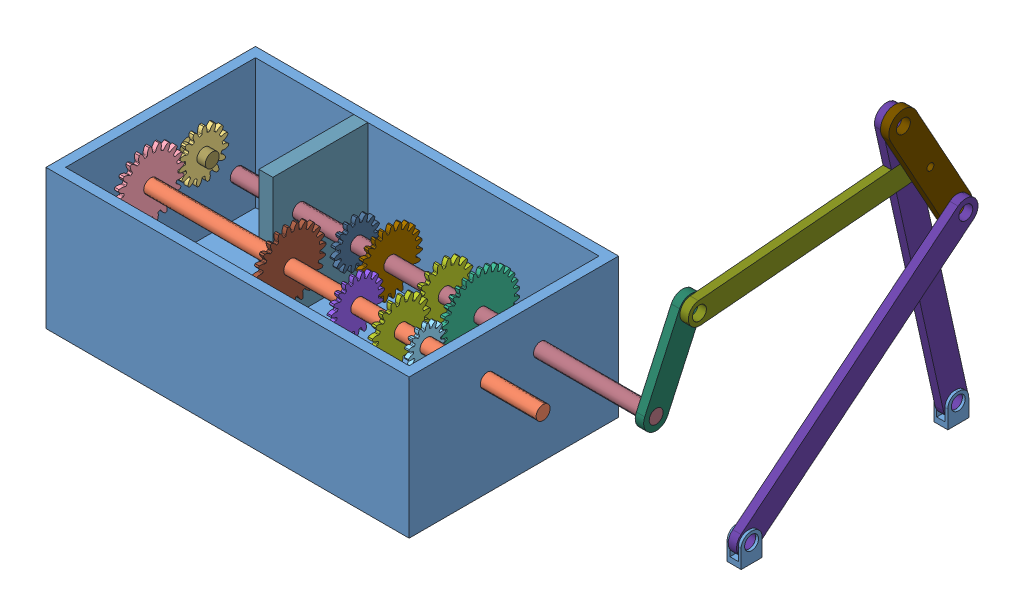
SolidWorks assembly Ensamblaje1 (1), configuration Predeterminado. Lengths in mm.
Overall size (362.85 223.11 312.81).
22 component instances, 19 part files, 42 mates.
Components (placement in the parent):
- caja-1: caja [Predeterminado] at (-217.3634 5.4035 0) size (260 100 150)
- Eje_30cm-1: Eje_30cm [Predeterminado] at (82.6366 25.4035 19.05) x (0 0.184444 0.982843) z (-1 0 0) size (10 10 300)
- E_15_12pd-2: E_15_12pd [Predeterminado] at (-198.3433 25.4035 -19.05) x (0 -0.65131 0.758812) z (-1 0 0) size (35.54 35.73 3)
- E_21_12pd-2: E_21_12pd [Predeterminado] at (-198.3634 25.4035 19.05) x (0 0.948662 0.316291) z (-1 0 0) size (48.58 48.71 3)
- E_14_15pd-2: E_14_15pd [Predeterminado] at (-0.5144 25.4035 19.05) x (0 0.297967 -0.954576) z (-1 0 0) size (26.84 26.84 3)
- E_31_15pd-2: E_31_15pd [Predeterminado] at (-0.1394 25.4035 -19.05) x (0 -0.987554 -0.157277) z (-1 0 0) size (55.79 55.86 3)
- E_18_12pd-1: E_18_12pd [Predeterminado] at (-25.5849 25.4035 -19.05) x (0 0.955422 0.295243) z (-1 0 0) size (42.34 42.34 3)
- E_18_12pd-2: E_18_12pd [Predeterminado] at (-18.9298 25.4035 19.05) x (0 -0.998788 -0.049227) z (-1 0 0) size (42.34 42.34 3)
- E_19_14pd-1: E_19_14pd [Predeterminado] at (-50.071 25.4035 19.05) x (0 -0.854783 0.518986) z (-1 0 0) size (37.93 38.05 3)
- E_23_14pd-1: E_23_14pd [Predeterminado] at (-64.5172 25.4035 -19.05) x (0 0.290606 -0.956843) z (-1 0 0) size (45.32 45.42 3)
- E_15_13pd-1: E_15_13pd [Predeterminado] at (-88.5172 25.4035 -19.05) x (0 -0.914548 -0.404477) z (-1 0 0) size (32.76 32.93 3)
- E_24_13pd-1: E_24_13pd [Predeterminado] at (-98.0912 25.4035 19.05) x (0 -0.999999 -0.001176) z (-1 0 0) size (50.75 50.75 3)
- Eje_300mm-1: Eje_300mm [Predeterminado] at (-192.3634 25.4035 -19.05) x (0 0 1) z (-1 0 0) size (10 10 25)
- Eje_300.2mm-1: Eje_300.2mm [Predeterminado] at (125.4828 25.4035 -19.05) x (0 -0.913785 0.406197) z (-1 0 0) size (10 10 300)
- Tapacentro-1: Tapacentro [Predeterminado] at (-129.9411 7.2523 -13.1723) x (0 0 1) z (-1 0 0) size (68 93 10)
- Eslabon1_BM-1: Eslabon1_BM [Predeterminado] at (119.4828 46.0248 -28.4902) x (0 0.909252 -0.416246) z (1 0 0) size (78 18 6)
- Eslabon2_BM-1: Eslabon2_BM [Predeterminado] at (131.4828 84.681 -98.1904) x (0 0.086854 -0.996221) z (-1 0 0) size (176 16 6)
- Eslabon1_Chevy-1: Eslabon1_Chevy [Predeterminado] at (131.4828 -34.4938 -220.2851) x (0 0.976303 0.216409) z (-1 0 0) size (217.53 17.53 6)
- Eslabon2_Chevy-1: Eslabon2_Chevy [Predeterminado] at (131.4828 92.0724 -204.4053) x (0 -0.875265 -0.483643) z (1 0 0) size (100.86 20.86 6)
- Eslabon1_Chevy-2: Eslabon1_Chevy [Predeterminado] at (137.4828 -46.4779 -92.7476) x (0 0.62945 -0.777041) z (1 0 0) size (217.53 17.53 6)
- Pasador_mecanismo-1: Pasador_mecanismo [Predeterminado] at (145.4828 -70.5444 -64.0193) x (0 -0.004066 0.999992) z (-1 0 0) size (15 20 10)
- Pasador_mecanismo-2: Pasador_mecanismo [Predeterminado] at (133.4828 -69.8938 -224.018) x (0 -0.004066 0.999992) z (-1 0 0) size (15 20 10)
Mates (geometry in assembly coordinates):
- Concéntrica7: concentric: cylinder of caja-1 through (42.6366 25.4035 19.05) axis (-1 0 0) radius 5; cylinder of Eje_30cm-1 through (-217.3634 25.4035 19.05) axis (1 0 0) radius 5
- Concéntrica10: concentric: cylinder of Eje_30cm-1 through (-217.3634 25.4035 19.05) axis (1 0 0) radius 5; cylinder of E_21_12pd-2 through (-198.3634 25.4035 19.05) axis (-1 0 0) radius 5
- Concéntrica11: concentric: cylinder of Eje_30cm-1 through (-217.3634 25.4035 19.05) axis (1 0 0) radius 5; cylinder of E_14_15pd-2 through (-0.5144 25.4035 19.05) axis (-1 0 0) radius 5
- Concéntrica13: concentric: cylinder of Eje_30cm-1 through (-217.3634 25.4035 19.05) axis (1 0 0) radius 5; cylinder of E_18_12pd-2 through (-18.9298 25.4035 19.05) axis (-1 0 0) radius 5
- Concéntrica15: concentric: cylinder of Eje_30cm-1 through (-217.3634 25.4035 19.05) axis (1 0 0) radius 5; cylinder of E_19_14pd-1 through (-50.071 25.4035 19.05) axis (-1 0 0) radius 5
- Concéntrica18: concentric: cylinder of Eje_30cm-1 through (-217.3634 25.4035 19.05) axis (1 0 0) radius 5; cylinder of E_24_13pd-1 through (-98.0912 25.4035 19.05) axis (-1 0 0) radius 5
- Concéntrica19: concentric: cylinder of caja-1 through (42.6366 25.4035 -19.05) axis (-1 0 0) radius 5; cylinder of Eje_300mm-1 through (-217.3634 25.4035 -19.05) axis (1 0 0) radius 5
- Coincidente1: coincident: circle of caja-1; circle of Eje_300mm-1
- Concéntrica20: concentric: cylinder of E_15_12pd-2 through (-198.3433 25.4035 -19.05) axis (-1 0 0) radius 5; cylinder of Eje_300mm-1 through (-217.3634 25.4035 -19.05) axis (1 0 0) radius 5
- Concéntrica22: concentric: cylinder of caja-1 through (42.6366 25.4035 -19.05) axis (-1 0 0) radius 5; cylinder of Eje_300.2mm-1 through (-174.5172 25.4035 -19.05) axis (1 0 0) radius 5
- Concéntrica23: concentric: cylinder of E_15_13pd-1 through (-88.5172 25.4035 -19.05) axis (-1 0 0) radius 5; cylinder of Eje_300.2mm-1 through (-174.5172 25.4035 -19.05) axis (1 0 0) radius 5
- Concéntrica24: concentric: cylinder of E_23_14pd-1 through (-64.5172 25.4035 -19.05) axis (-1 0 0) radius 5; cylinder of Eje_300.2mm-1 through (-174.5172 25.4035 -19.05) axis (1 0 0) radius 5
- Concéntrica25: concentric: cylinder of E_18_12pd-1 through (-25.5849 25.4035 -19.05) axis (-1 0 0) radius 5; cylinder of Eje_300.2mm-1 through (-174.5172 25.4035 -19.05) axis (1 0 0) radius 5
- Concéntrica26: concentric: cylinder of E_31_15pd-2 through (-0.1394 25.4035 -19.05) axis (-1 0 0) radius 5; cylinder of Eje_300.2mm-1 through (-174.5172 25.4035 -19.05) axis (1 0 0) radius 5
- Distancia1: distance = 214 mm: plane of Eje_300.2mm-1 through (125.4828 25.4035 -19.05) normal (-1 0 0); plane of E_15_13pd-1 through (-88.5172 25.4035 -19.05) normal (-1 0 0)
- Distancia2: distance = 190 mm: plane of Eje_300.2mm-1 through (125.4828 25.4035 -19.05) normal (-1 0 0); plane of E_23_14pd-1 through (-64.5172 25.4035 -19.05) normal (-1 0 0)
- Distancia3: distance = 151.0677 mm: plane of Eje_300.2mm-1 through (125.4828 25.4035 -19.05) normal (-1 0 0); plane of E_18_12pd-1 through (-25.5849 25.4035 -19.05) normal (-1 0 0)
- Distancia4: distance = 125.6222 mm: plane of E_31_15pd-2 through (-0.1394 25.4035 -19.05) normal (-1 0 0); plane of Eje_300.2mm-1 through (125.4828 25.4035 -19.05) normal (-1 0 0)
- Concéntrica27: concentric: cylinder of Eje_300.2mm-1 through (-174.5172 25.4035 -19.05) axis (1 0 0) radius 5; cylinder of Tapacentro-1 through (-129.9411 25.4035 -19.05) axis (-1 0 0) radius 5
- Distancia5: distance = 281 mm: plane of Eje_30cm-1 through (82.6366 25.4035 19.05) normal (-1 0 0); plane of E_21_12pd-2 through (-198.3634 25.4035 19.05) normal (-1 0 0)
- Distancia6: distance = 180.7277 mm: plane of Eje_30cm-1 through (82.6366 25.4035 19.05) normal (-1 0 0); plane of E_24_13pd-1 through (-98.0912 25.4035 19.05) normal (-1 0 0)
- Distancia7: distance = 132.7076 mm: plane of Eje_30cm-1 through (82.6366 25.4035 19.05) normal (-1 0 0); plane of E_19_14pd-1 through (-50.071 25.4035 19.05) normal (-1 0 0)
- Distancia8: distance = 101.5663 mm: plane of Eje_30cm-1 through (82.6366 25.4035 19.05) normal (-1 0 0); plane of E_18_12pd-2 through (-18.9298 25.4035 19.05) normal (-1 0 0)
- Distancia9: distance = 83.151 mm: plane of Eje_30cm-1 through (82.6366 25.4035 19.05) normal (-1 0 0); plane of E_14_15pd-2 through (-0.5144 25.4035 19.05) normal (-1 0 0)
- Distancia10: distance = 5.9798 mm: plane of Eje_300mm-1 through (-192.3634 25.4035 -19.05) normal (-1 0 0); plane of E_15_12pd-2 through (-198.3433 25.4035 -19.05) normal (-1 0 0)
- Relación de posición de engranaje3: gear = 35.56 : 25.4 mm: cylinder of E_15_12pd-2 through (-198.3433 25.4035 -19.05) axis (-1 0 0) radius 13.2207; cylinder of E_21_12pd-2 through (-198.3634 25.4035 19.05) axis (-1 0 0) radius 19.558
- Relación de posición de engranaje4: gear = 40.64 : 25.4 mm: cylinder of E_15_13pd-1 through (-88.5172 25.4035 -19.05) axis (-1 0 0) radius 12.192; cylinder of E_24_13pd-1 through (-98.0912 25.4035 19.05) axis (-1 0 0) radius 20.955
- Coincidente13: coincident: circle of caja-1; circle of Eje_30cm-1
- Relación de posición de engranaje6: gear = 30.734 : 25.4 mm: cylinder of E_23_14pd-1 through (-64.5172 25.4035 -19.05) axis (-1 0 0) radius 18.542; cylinder of E_19_14pd-1 through (-50.071 25.4035 19.05) axis (-1 0 0) radius 14.986
- Relación de posición de engranaje7: gear = 25.4 : 25.4 mm: cylinder of E_18_12pd-1 through (-25.5849 25.4035 -19.05) axis (-1 0 0) radius 16.51; cylinder of E_18_12pd-2 through (-18.9298 25.4035 19.05) axis (-1 0 0) radius 16.51
- Relación de posición de engranaje8: gear = 25.4 : 56.134 mm: cylinder of E_31_15pd-2 through (-0.1394 25.4035 -19.05) axis (-1 0 0) radius 24.13; cylinder of E_14_15pd-2 through (-0.5144 25.4035 19.05) axis (-1 0 0) radius 9.779
- Coincidente28: coincident: circle of Eslabon1_Chevy-2; circle of Pasador_mecanismo-1
- Coincidente29: coincident: circle of Eslabon1_Chevy-1; circle of Pasador_mecanismo-2
- Coincidente30: coincident: plane of Pasador_mecanismo-1 through (145.4828 -70.5444 -64.0193) normal (0 0.999992 0.004066); plane of Pasador_mecanismo-2 through (133.4828 -69.8938 -224.018) normal (0 0.999992 0.004066)
- Coincidente34: coincident: circle of Eslabon2_Chevy-1; circle of Eslabon1_Chevy-2
- Coincidente35: coincident: circle of Eslabon1_Chevy-1; circle of Eslabon2_Chevy-1
- Coincidente36: coincident: plane of Pasador_mecanismo-1 through (145.4828 -70.5444 -64.0193) normal (0 0.999992 0.004066); plane of Pasador_mecanismo-2 through (133.4828 -69.8938 -224.018) normal (0 0.999992 0.004066)
- Distancia14: distance = 160 mm: plane of Pasador_mecanismo-2 through (133.4828 -69.8938 -224.018) normal (0 -0.004066 0.999992); plane of Pasador_mecanismo-1 through (145.4828 -70.5444 -64.0193) normal (0 -0.004066 0.999992)
- Coincidente38: coincident: circle of Eslabon2_BM-1; circle of Eslabon2_Chevy-1
- Concéntrica31: concentric: cylinder of Eje_300.2mm-1 through (-174.5172 25.4035 -19.05) axis (1 0 0) radius 5; cylinder of Eslabon1_BM-1 through (125.4828 25.4035 -19.05) axis (-1 0 0) radius 5
- Coincidente39: coincident: circle of Eslabon1_BM-1; circle of Eslabon2_BM-1
- Coincidente40: coincident: circle of Eje_300.2mm-1; circle of Eslabon1_BM-1
